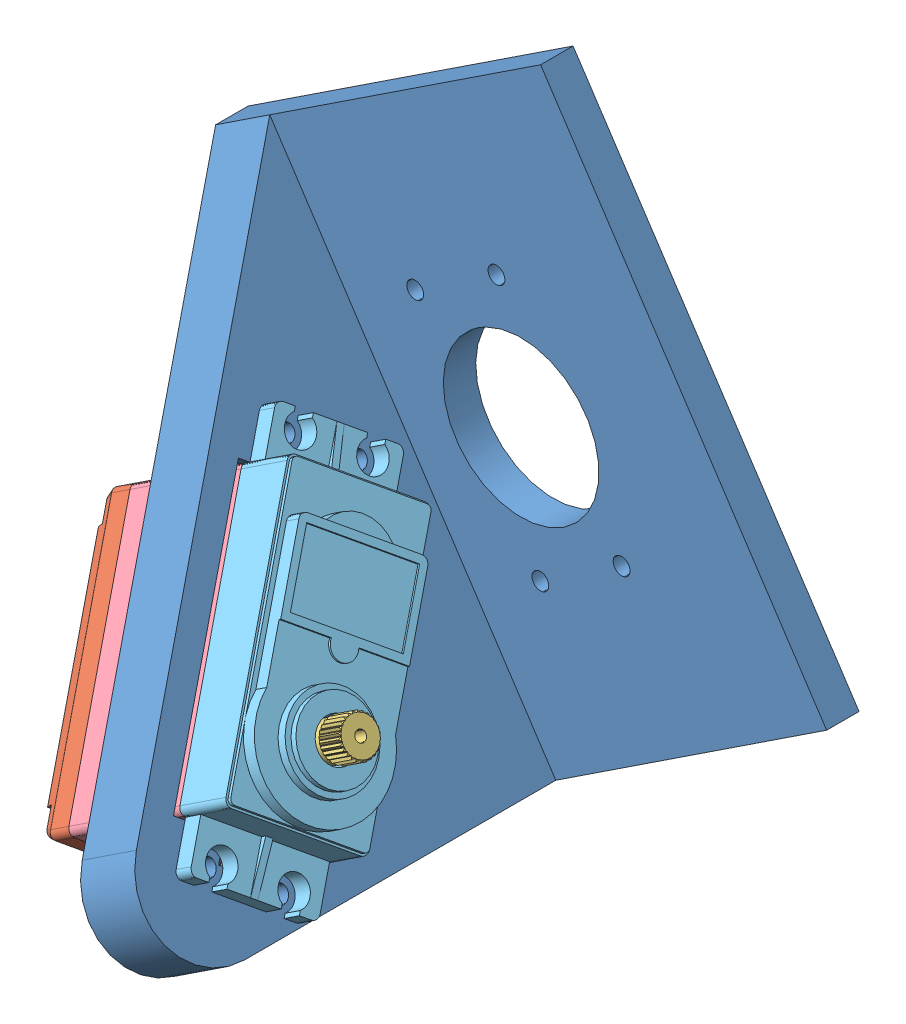
SolidWorks assembly Złożenie8, configuration Domyślna. Lengths in mm.
Overall size (94.14 109.68 62.96).
6 component instances, 5 part files, 3 mates.
Components (placement in the parent):
- Mocowanie-1: Mocowanie [Domyślna] at (40.1439 -61.9925 64.2126) x (-0.550863 0.834596 0) z (0 0 1) size (80 60 62.96)
- MG_996R-1: MG_996R [Domyślna] at (-24.4927 -92.4165 92.8752) x (0.362745 -0.549585 -0.752577) z (-0.414566 0.628098 -0.658505) size (19.93 44.4 54.6)
  - Base-1: Base [Domyślna] at (12.6939 -23.8049 -20.4733) size (19.93 6.4 40.73)
  - Eje-1: Eje [Domyślna] at (12.6939 -50.7049 -30.7733) x (-0.837169 0 -0.546944) z (-0.546944 0 0.837169) size (5.78 17.5 5.8)
  - Medio-1: Medio [Domyślna] at (12.6939 -30.2049 -20.4733) size (19.8 20.5 40.6)
  - Top-1: Top [Domyślna] at (12.6939 -59.7049 -20.4733) x (-1 0 0) z (0 0 1) size (19.8 13.2 54.6)
Mates (geometry in assembly coordinates):
- Koncentryczne214: concentric anti-aligned: cylinder of MG_996R-1/Top-1 through (45.3867 -101.1595 109.4312) axis (-0.834596 -0.550863 0) radius 2.2; cylinder of Mocowanie-1 through (43.0499 -102.7019 109.4312) axis (0.834596 0.550863 0) radius 1.3
- Koncentryczne215: concentric aligned: cylinder of Mocowanie-1 through (39.4224 -97.2061 116.957) axis (0.834596 0.550863 0) radius 1.3; cylinder of MG_996R-1/Top-1 through (41.7593 -95.6637 116.957) axis (0.834596 0.550863 0) radius 2.2
- Wspólnie193: coincident anti-aligned: plane of Mocowanie-1 through (23.452 -73.0098 64.2126) normal (0.834596 0.550863 0); plane of MG_996R-1/Top-1 through (30.9176 -84.3207 96.8039) normal (-0.834596 -0.550863 0)
